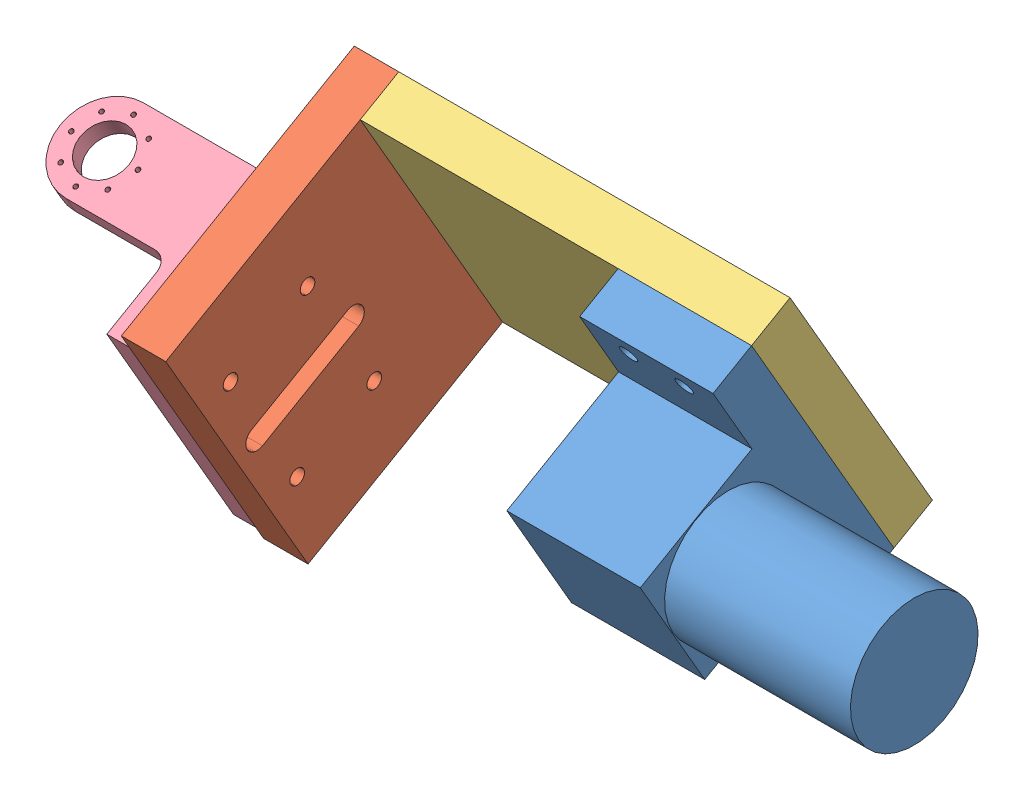
SolidWorks assembly Assem3, configuration Default. Lengths in mm.
Overall size (177.8 85.68 84.39).
4 component instances, 4 part files, 10 mates.
Components (placement in the parent):
- camara-1: camara [Default] at (78.2016 12.25 -76.7472) x (0 0.866025 0.5) z (0 -0.5 0.866025) size (64 71.8 40)
- L-parte1-1: L-parte1 [Default] at (-4.7984 44.9628 -69.4074) x (0 -0.866025 -0.5) z (-1 0 0) size (64 60.5 10)
- L-parte2-1: L-parte2 [Default] at (-4.7984 44.9628 -69.4074) x (0 -0.866025 -0.5) z (-1 0 0) size (64 10 88)
- suporte-1: suporte [Default] at (-4.7984 -4 -48.6013) x (0 0.866025 0.5) z (1 0 0) size (57 36 38)
Mates (geometry in assembly coordinates):
- Coincident1: coincident anti-aligned: plane of camara-1 through (78.2016 44.31 -76.7472) normal (0 0.5 -0.866025); plane of L-parte2-1 through (93.2016 16.5972 -92.7472) normal (0 -0.5 0.866025)
- Concentric2: concentric aligned: circle of camara-1; circle of L-parte2-1
- Concentric3: concentric anti-aligned: circle of camara-1; circle of L-parte2-1
- Coincident2: coincident aligned: plane of L-parte1-1 through (5.2016 -8.6528 -49.0129) normal (0 -0.5 0.866025); plane of suporte-1 through (-9.7984 -5.6217 -47.2629) normal (0 -0.5 0.866025)
- Coincident3: coincident anti-aligned: plane of L-parte1-1 through (-4.7984 -8.6528 -49.0129) normal (-1 0 0); plane of suporte-1 through (-4.7984 28.06 -48.6013) normal (1 0 0)
- Concentric4: concentric aligned: circle of L-parte1-1; circle of suporte-1
- Concentric6: concentric anti-aligned: circle of L-parte1-1; circle of L-parte2-1
- Concentric7: concentric aligned: circle of L-parte1-1; circle of L-parte2-1
- Coincident4: coincident anti-aligned: plane of L-parte1-1 through (5.2016 16.5972 -92.7472) normal (1 0 0); plane of L-parte2-1 through (5.2016 -8.6528 -49.0129) normal (-1 0 0)
- Coincident7: coincident: line of camara-1 through (135.0016 0 -55.5295) axis (-1 0 0); plane of assembly
